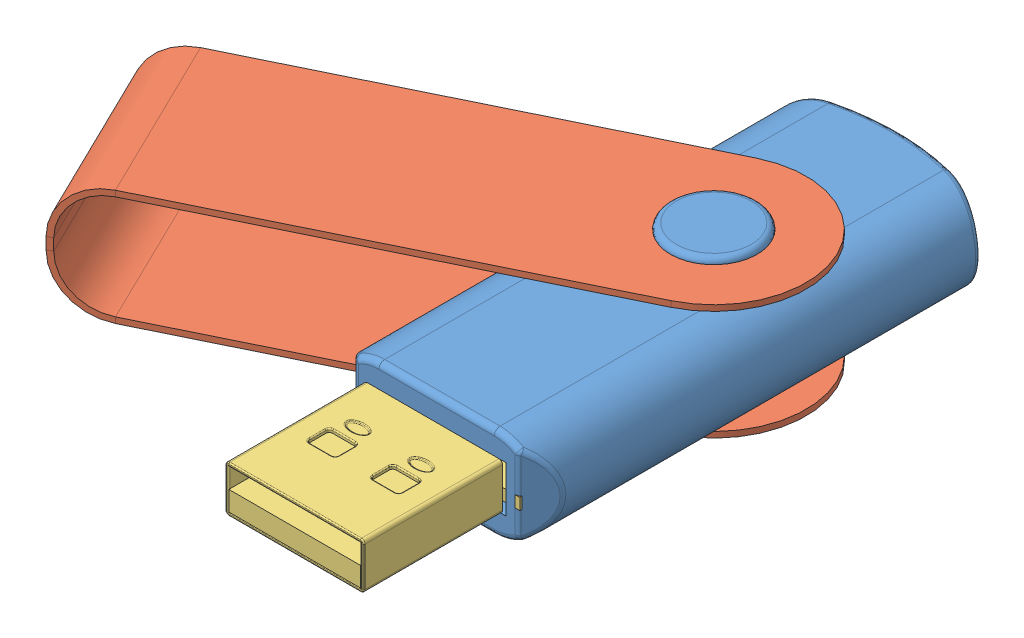
SolidWorks assembly Assem1, configuration Default. Lengths in mm.
Overall size (50.61 10.5 52).
3 component instances, 3 part files, 13 mates.
Components (placement in the parent):
- Part1_stick-1: Part1_stick [Default] at (1.3582 9.2337 45.7739) size (18 10 40)
- Part3_stick-1: Part3_stick [Default] at (12.0554 8.2337 25.4577) x (-0.898811 0 0.438336) z (-0.438336 0 -0.898811) size (48.5 10 16)
- Part2_stick-1: Part2_stick [Default] at (1.0582 12.2337 29.7739) size (15 4.05 44)
Mates (geometry in assembly coordinates):
- Concentric3: concentric aligned: cylinder of Part1_stick-1 through (1.3582 18.2337 21.7739) axis (0 -1 0) radius 3.75; cylinder of Part3_stick-1 through (1.3582 28.3403 21.7739) axis (0 -1 0) radius 3.75
- Concentric5: concentric aligned: cylinder of Part1_stick-1 through (1.3582 18.2337 21.7739) axis (0 -1 0) radius 3.75; cylinder of Part3_stick-1 through (1.3582 28.3403 21.7739) axis (0 -1 0) radius 3.75
- Concentric7: concentric aligned: cylinder of Part1_stick-1 through (1.3582 18.2337 21.7739) axis (0 -1 0) radius 3.75; cylinder of Part3_stick-1 through (1.3582 28.3403 21.7739) axis (0 -1 0) radius 3.75; circle of Part1_stick-1
- Concentric8: concentric aligned: cylinder of Part3_stick-1 through (1.3582 28.3403 21.7739) axis (0 -1 0) radius 3.75; cylinder of Part1_stick-1 through (1.3582 18.2337 21.7739) axis (0 -1 0) radius 3.75
- Concentric9: concentric aligned: cylinder of Part3_stick-1 through (1.3582 28.3403 21.7739) axis (0 -1 0) radius 3.75; circle of Part1_stick-1
- Tangent3: tangent aligned: torus of Part1_stick-1; cylinder of Part3_stick-1 through (1.3582 28.3403 21.7739) axis (0 -1 0) radius 3.75
- Tangent4: tangent aligned: torus of Part1_stick-1; cylinder of Part3_stick-1 through (1.3582 28.3403 21.7739) axis (0 -1 0) radius 3.75
- Concentric10: concentric anti-aligned: circle of Part1_stick-1; circle of Part3_stick-1
- Concentric11: concentric anti-aligned: cylinder of Part1_stick-1 through (1.3582 18.2337 21.7739) axis (0 -1 0) radius 3.75; circle of Part3_stick-1
- Concentric12: concentric aligned: cylinder of Part1_stick-1 through (1.3582 18.2337 21.7739) axis (0 -1 0) radius 3.75; cylinder of Part3_stick-1 through (1.3582 28.3403 21.7739) axis (0 -1 0) radius 3.75
- Tangent5: tangent aligned: torus of Part1_stick-1; cylinder of Part3_stick-1 through (1.3582 28.3403 21.7739) axis (0 -1 0) radius 3.75
- Coincident2: coincident anti-aligned: plane of Part1_stick-1 through (1.3582 17.2337 27.0239) normal (0 1 0); plane of Part3_stick-1 through (-34.5056 17.2337 30.3635) normal (0 -1 0)
- Coincident7: coincident anti-aligned: plane of Part1_stick-1 through (-5.6418 17.2337 45.7739) normal (0 0 1); plane of Part2_stick-1 through (6.7582 14.9337 45.7739) normal (0 0 -1)
